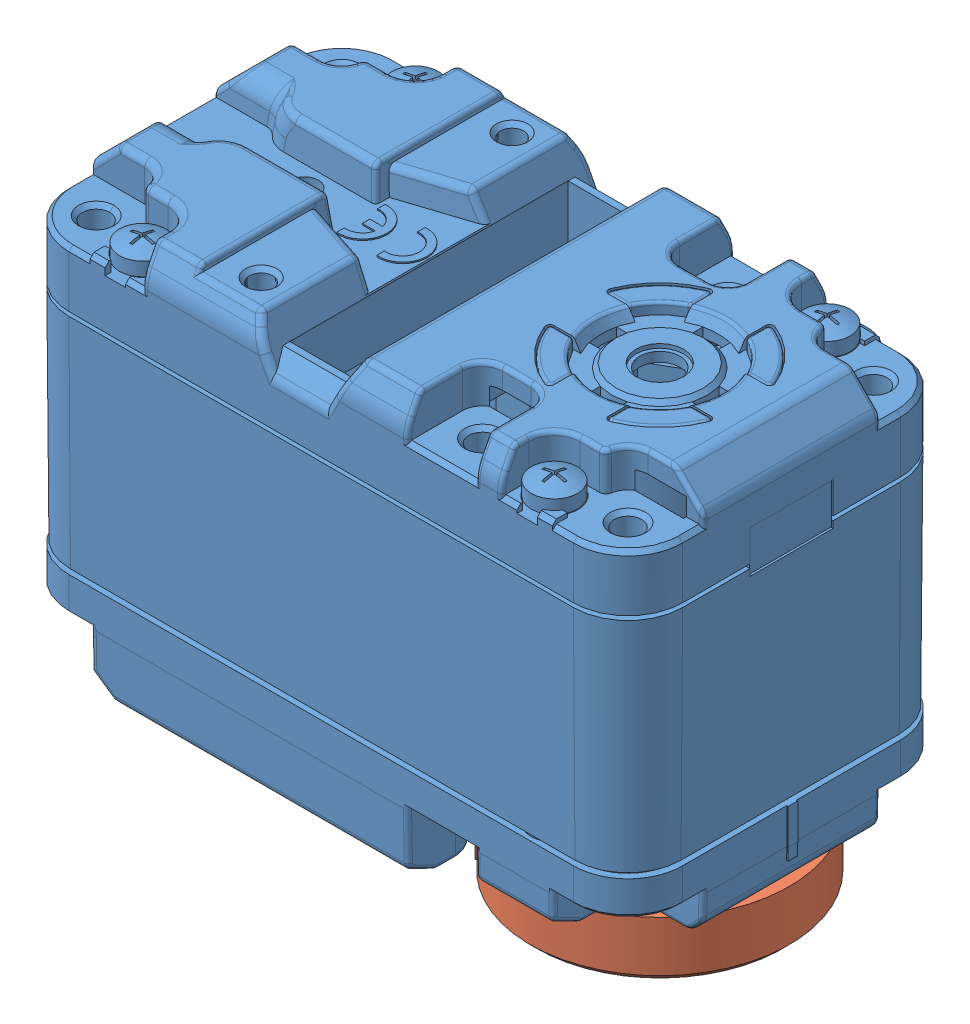
SolidWorks assembly Herkulex Assem, configuration Default. Lengths in mm.
Overall size (48.93 35.02 26.89).
2 component instances, 2 part files, 2 mates.
Components (placement in the parent):
- Herkulex-1: Herkulex [Default] at (-3.5446 3.597 -11.0386) size (45.29 35.02 24.91)
- Herkulex horn-1: Herkulex horn [Default] at (41.9148 3.997 -28.356) x (-0.746547 0 0.665333) z (-0.665333 0 -0.746547) size (19.1 6.4 19)
Mates (geometry in assembly coordinates):
- Concentric1: concentric anti-aligned: cylinder of Herkulex-1 through (22.4836 -6.003 -11.0386) axis (0 1 0) radius 1.25; cylinder of Herkulex horn-1 through (22.4836 -6.603 -11.0386) axis (0 -1 0) radius 3.25
- Coincident1: coincident anti-aligned: plane of Herkulex-1 through (32.1554 -2.403 0.9614) normal (0 -1 0); plane of Herkulex horn-1 through (22.4836 -2.403 -11.0386) normal (0 1 0)
